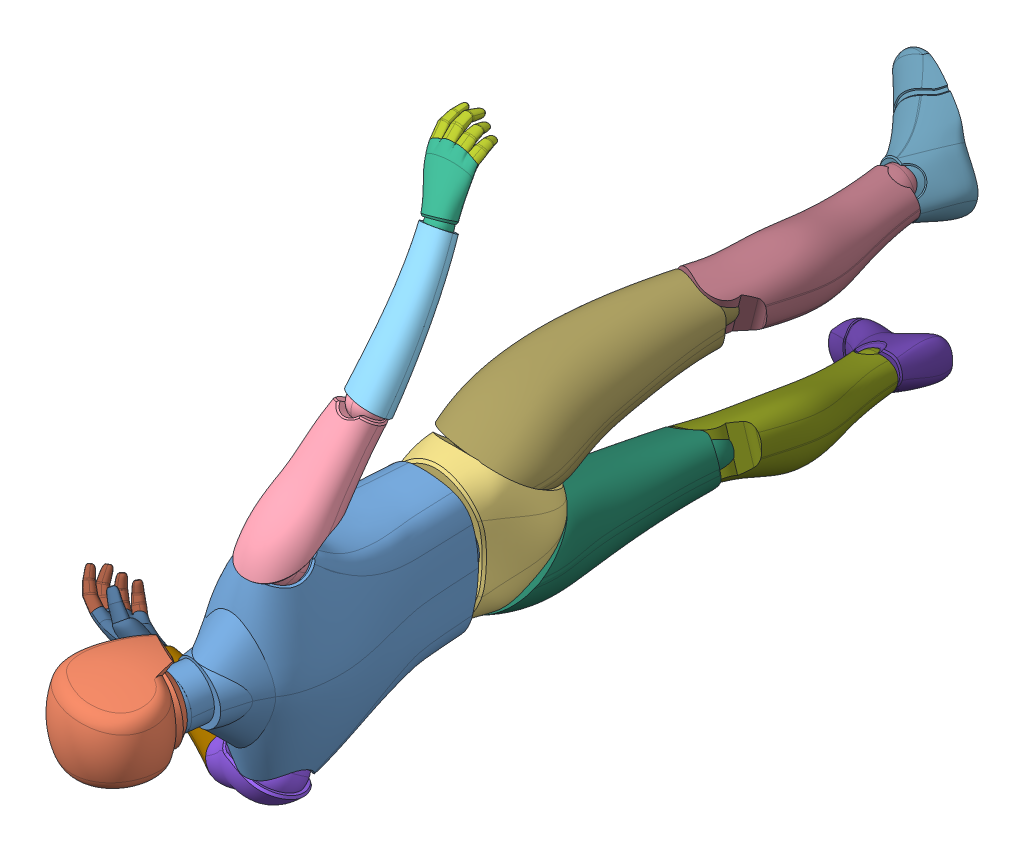
SolidWorks assembly Articulated_Dummy, configuration Default. Lengths in mm.
Overall size (1027.37 1566.53 1879.25).
22 component instances, 17 part files, 12 mates.
Components (placement in the parent):
- Torso-1: Torso [Default] at origin size (276.17 406.18 676.75)
- Head-1: Head [Default] at (272.4966 0 13.9002) x (0.984808 0 0.173648) z (-0.173648 0 0.984808) size (223.51 154.11 248.99)
- Pelvis-1: Pelvis [Default] at (-54.8593 -0.0047 3.2616) x (0.998539 0 -0.054038) z (0.054038 0 0.998539) size (220.9 294.19 237.82)
- RH^Articulated_Dummy-1: RH^Articulated_Dummy [Default] at (1280.9669 169.0938 650.7723) x (0.41235 -0.43558 0.800149) z (-0.903162 -0.080302 0.421723) size (756.32 500.37 408.62) (virtual)
  - UpperArm_R-1: UpperArm_R [Default] at (-1109.0028 653.6539 837.3286) x (0.502988 0.098858 -0.858621) z (0.787204 -0.462524 0.407899) size (145.29 112.21 352.1)
  - LowerArm_R-1: LowerArm_R [Default] at (-1162.6476 523.6435 891.7138) x (0.439968 0.145247 -0.886189) z (0.858166 -0.358703 0.367264) size (97.1 110.82 304.02)
  - Hand_R-1: Hand_R [Default] at (-1163.3332 658.0805 957.6873) x (0.391774 0.104812 -0.914072) z (0.818093 -0.494278 0.29396) size (143.51 200.25 239.15)
    - Hand_R-1: Hand_R [Default] at origin size (143.51 200.25 232.94)
    - Fingers_R-1: Fingers_R [Default] at origin size (103.08 62.21 73.67)
- UpperArm_L-1: UpperArm_L [Default] at (-1099.3686 -603.7857 779.0068) x (0.576205 -0.390843 -0.717795) z (0.802812 0.435317 0.407421) size (149.95 126.7 354.11)
- LowerArm_L-1: LowerArm_L [Default] at (-1142.7508 36.6231 953.4595) x (0.416152 0.090277 -0.904802) z (0.903761 -0.150682 0.400639) size (97.1 110.82 304.02)
- Hand_L-1: Hand_L [Default] at (-1102.2665 -3.2175 802.0206) x (0.400695 -0.340847 -0.850451) z (0.891217 -0.070337 0.448091) size (143.54 200.25 239.15)
  - Hand_L-1: Hand_L [Default] at origin size (143.54 200.25 232.94)
  - Fingers_L-1: Fingers_L [Default] at origin size (103.08 62.28 73.68)
- RL^Articulated_Dummy-1: RL^Articulated_Dummy [Default] at (871.9212 461.2548 884.4349) x (-0.173124 0.343457 0.923074) z (-0.863784 -0.503229 0.025237) size (978.55 724.54 335.77) (virtual)
  - UpperLeg_R-1: UpperLeg_R [Default] at (-794.9105 467.1364 932.2857) x (-0.237412 -0.59596 -0.767116) z (0.890194 -0.449571 0.073762) size (212.64 165.47 563.01)
  - LowerLeg_R-1: LowerLeg_R [Default] at (-812.0002 418.5436 918.219) x (-0.133651 -0.539864 -0.831074) z (0.924974 -0.368989 0.090943) size (159.05 194.06 506.09)
  - Foot_R-1: Foot_R [Default] at (-799.6569 429.8253 937.4483) x (-0.051043 -0.817163 -0.574143) z (0.982487 -0.144243 0.117951) size (250.01 160.41 191.51)
- LL^Articulated_Dummy-1: LL^Articulated_Dummy [Default] at (857.9052 -471.439 774.7148) x (-0.043726 -0.3247 0.944806) z (-0.846701 0.514006 0.137462) size (982.9 694.42 400.7) (virtual)
  - UpperLeg_L-1: UpperLeg_L [Default] at (-826.6454 -387.1401 868.6587) x (-0.136474 0.653159 -0.744821) z (0.92258 0.357678 0.144615) size (212.64 165.47 563.01)
  - LowerLeg_L-1: LowerLeg_L [Default] at (-822.6454 -401.7014 865.3101) x (-0.14989 0.639882 -0.753713) z (0.908575 0.389775 0.150221) size (159.05 194.91 471.32)
  - Foot_L-1: Foot_L [Default] at (-825.7183 -396.2605 859.2726) x (-0.072818 0.670091 -0.738698) z (0.921539 0.328446 0.207099) size (250.8 160.43 191.19)
Mates (geometry in assembly coordinates):
- Coincident1: coincident: point of Torso-1; point of Head-1
- Parallel1: parallel aligned: plane of Head-1 through (272.4966 0 13.9002) normal (0 1 0); plane of assembly through (0 0 0) normal (0 1 0)
- LimitAngle1: limit planar angle = 0.174533 rad aligned: plane of Head-1 through (272.4966 0 13.9002) normal (-0.173648 0 0.984808); plane of assembly through (0 0 0) normal (0 0 1)
- Coincident5: coincident: point of Torso-1; point of Pelvis-1
- Parallel3: parallel aligned: plane of Pelvis-1 through (-54.8593 -0.0047 3.2616) normal (0 1 0); plane of assembly through (0 0 0) normal (0 1 0)
- LimitAngle2: limit planar angle = 0.054064 rad aligned: plane of Pelvis-1 through (-54.8593 -0.0047 3.2616) normal (0.054038 0 0.998539); plane of Torso-1 through (0 0 0) normal (0 0 1)
- Coincident9: coincident: point of UpperArm_L-1; point of Torso-1
- Coincident10: coincident: point of UpperArm_L-1; point of LowerArm_L-1
- Coincident11: coincident: point of LowerArm_L-1; point of Hand_L-1
- Coincident18: coincident: point of Assem1^Articulated_Dummy-1/UpperLeg_R-1; point of Pelvis-1
- Coincident19: coincident: point of Pelvis-1; point of Assem2^Articulated_Dummy-1/UpperLeg_L-1
- Coincident20: coincident: point of Assem3^Articulated_Dummy-1/UpperArm_R-1; point of Torso-1
